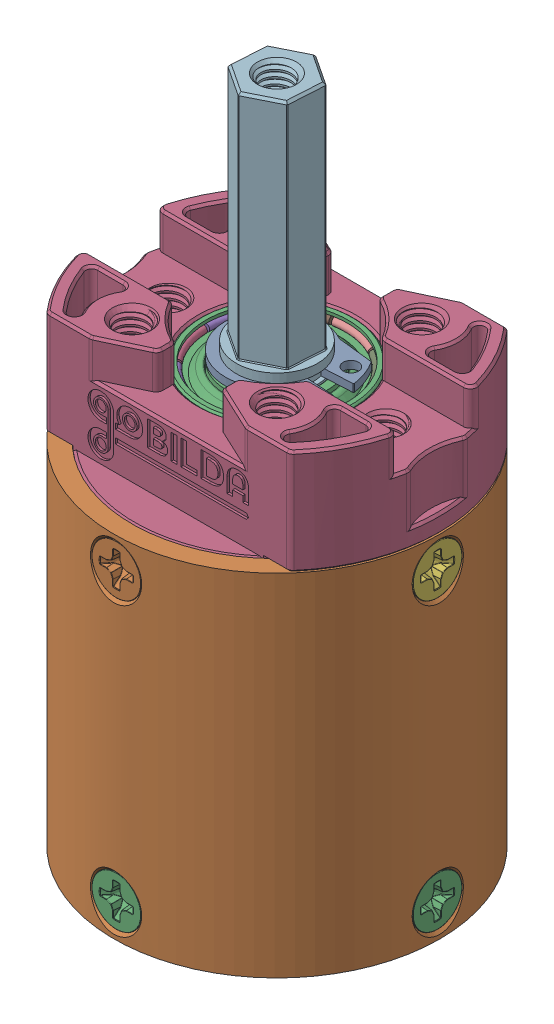
SolidWorks assembly Simple, configuration Default. Lengths in mm.
Overall size (36 73.8 35.96).
15 component instances, 7 part files, 0 mates.
Components (placement in the parent):
- 5303 Gearbox Base-1: 5303 Gearbox Base [Default] at (-58.7206 21.0354 14.7927) size (31.9 5.6 31.9)
- 5303 Gearbox Barrel (4 stage, simple)_Gear Blank-1: 5303 Gearbox Barrel (4 stage, simple)_Gear Blank [Default] at (-58.7206 99.2654 14.7927) x (1 0 0) z (0 -1 0) size (35.96 35.96 38.7)
- 5303 Gearbox Barrel Screw (M3 x 8mm length Flat Head)_92010A118-1: 5303 Gearbox Barrel Screw (M3 x 8mm length Flat Head)_92010A118 [Default] at (-58.7206 24.5354 30.8757) x (0.002439 -0.999997 0) z (0 0 1) size (5.46 5.46 8.05)
- 5303 Gearbox Face-1: 5303 Gearbox Face [Default] at (-58.7206 54.2354 14.7927) size (36 17.1 31.9)
- 5303 Gearbox Bearing-1: 5303 Gearbox Bearing [Default] at (-58.7206 62.3354 14.7927) size (17 5 17)
- 5303 Gearbox Shaft (23.5mm Length, Simple)-1: 5303 Gearbox Shaft (23.5mm Length, Simple) [Default] at (-58.7206 50.8754 14.7927) x (0.894773 0 -0.44652) z (0.44652 0 0.894773) size (8.97 40.6 8.97)
- 5303 Gearbox Snap Ring-1: 5303 Gearbox Snap Ring [Default] at (-58.7206 67.4104 14.7927) x (0 1 0) z (0 0 1) size (0.85 13.06 10.66)
- 5303 Gearbox Barrel Screw (M3 x 8mm length Flat Head)_92010A118-2: 5303 Gearbox Barrel Screw (M3 x 8mm length Flat Head)_92010A118 [Default] at (-58.7206 56.2354 30.8757) x (-0.002439 -0.999997 0) z (0 0 1) size (5.46 5.46 8.05)
- 5303 Gearbox Barrel Screw (M3 x 8mm length Flat Head)_92010A118-3: 5303 Gearbox Barrel Screw (M3 x 8mm length Flat Head)_92010A118 [Default] at (-42.6376 24.5354 14.7927) x (0 -0.999997 -0.002439) z (1 0 0) size (5.46 5.46 8.05)
- 5303 Gearbox Barrel Screw (M3 x 8mm length Flat Head)_92010A118-4: 5303 Gearbox Barrel Screw (M3 x 8mm length Flat Head)_92010A118 [Default] at (-58.7206 24.5354 -1.2903) x (-0.002439 -0.999997 0) z (0 0 -1) size (5.46 5.46 8.05)
- 5303 Gearbox Barrel Screw (M3 x 8mm length Flat Head)_92010A118-5: 5303 Gearbox Barrel Screw (M3 x 8mm length Flat Head)_92010A118 [Default] at (-74.8037 24.5354 14.7927) x (0 -0.999997 0.002439) z (-1 0 0) size (5.46 5.46 8.05)
- 5303 Gearbox Barrel Screw (M3 x 8mm length Flat Head)_92010A118-6: 5303 Gearbox Barrel Screw (M3 x 8mm length Flat Head)_92010A118 [Default] at (-42.6376 56.2354 14.7927) x (0 -0.999997 0.002439) z (1 0 0) size (5.46 5.46 8.05)
- 5303 Gearbox Barrel Screw (M3 x 8mm length Flat Head)_92010A118-7: 5303 Gearbox Barrel Screw (M3 x 8mm length Flat Head)_92010A118 [Default] at (-58.7206 56.2354 -1.2903) x (0.002439 -0.999997 0) z (0 0 -1) size (5.46 5.46 8.05)
- 5303 Gearbox Barrel Screw (M3 x 8mm length Flat Head)_92010A118-8: 5303 Gearbox Barrel Screw (M3 x 8mm length Flat Head)_92010A118 [Default] at (-74.8037 56.2354 14.7927) x (0 -0.999997 -0.002439) z (-1 0 0) size (5.46 5.46 8.05)
- 5303 Gearbox Bearing-2: 5303 Gearbox Bearing [Default] at (-58.7206 54.2354 14.7927) size (17 5 17)
